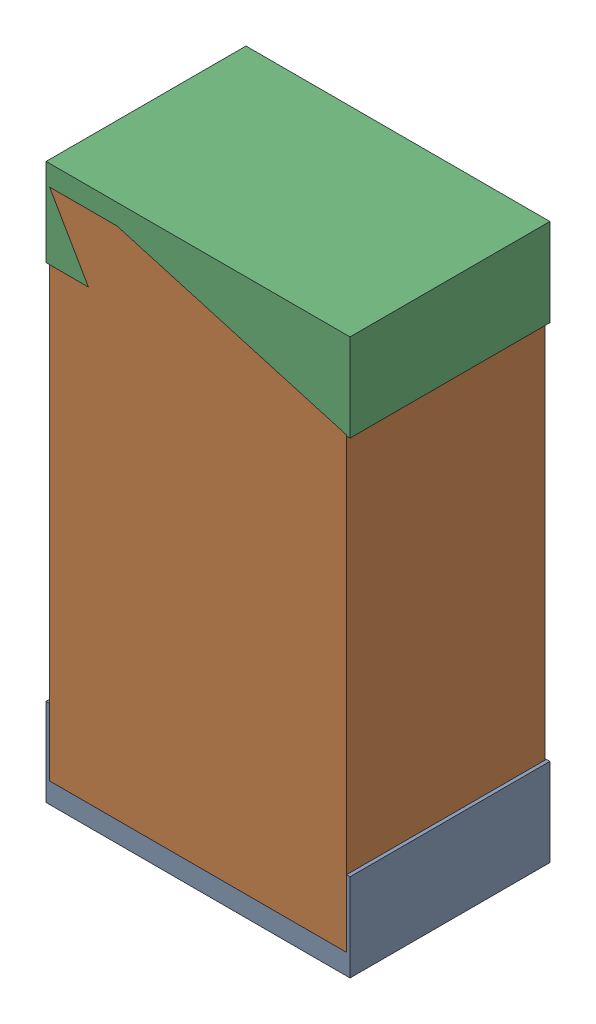
SolidWorks assembly R5, configuration Default. Lengths in mm.
Overall size (1.3 2.38 0.85).
6 component instances, 2 part files, 0 mates.
Components (placement in the parent):
- 402662288-1: 402662288 [Default] at (154.305 101.616 -1.9574) size (1.3 0.38 0.85)
  - Extruded_16-1: Extruded_16 [Default] at origin size (1.3 0.38 0.85)
- 402662416-1: 402662416 [Default] at (154.305 102.616 -1.9524) size (1.27 2.2 0.85)
  - Extruded_17-1: Extruded_17 [Default] at origin size (1.27 2.2 0.85)
- 402662288-2: 402662288 [Default] at (154.305 103.616 -1.9574) size (1.3 0.38 0.85)
  - Extruded_16-1: Extruded_16 [Default] at origin size (1.3 0.38 0.85)
